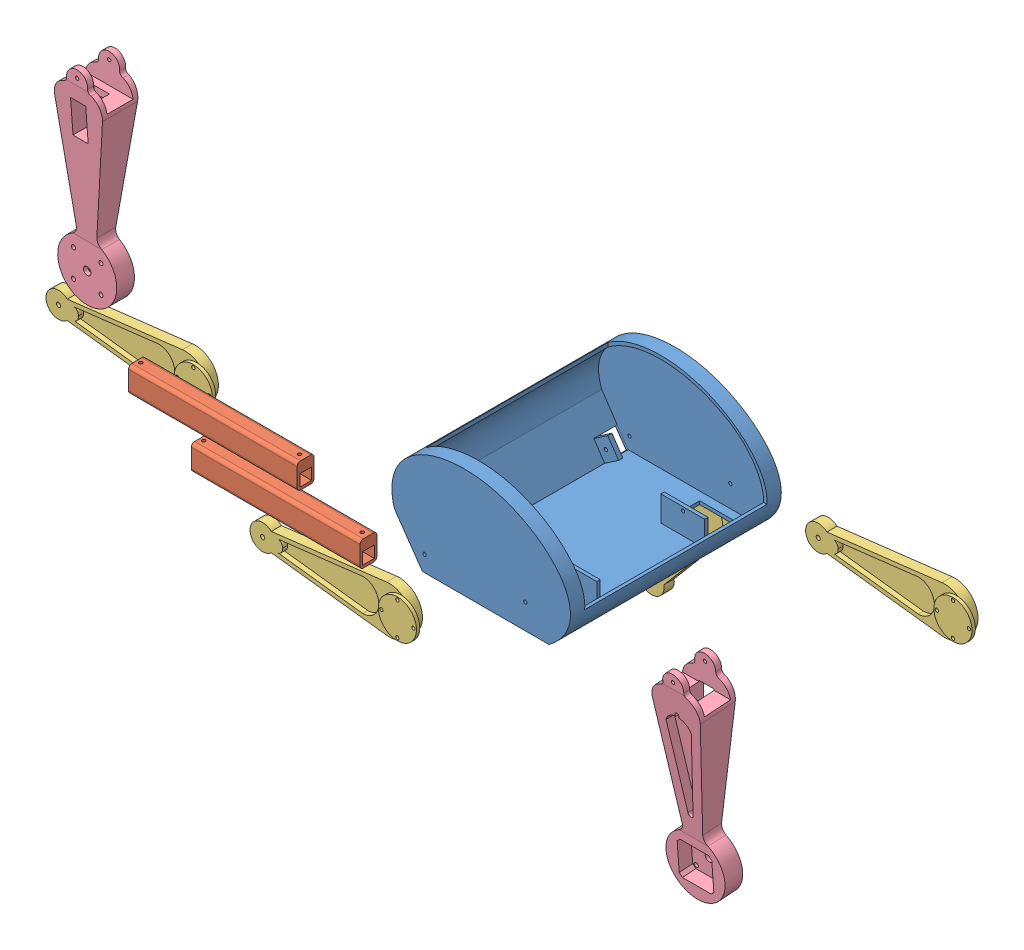
SolidWorks assembly Assem1, configuration Default. Lengths in mm.
Overall size (967.8 599.19 396.07).
9 component instances, 4 part files, 3 mates.
Components (placement in the parent):
- head2-1: head2 [Default] at (63.3878 149.356 194.8551) size (224.14 133.43 250)
- rod-1: rod [Default] at (-170.6013 277.7549 524.6912) size (200 30 20)
- rod-2: rod [Default] at (-120.5483 210.5086 500.3326) size (200 30 20)
- upleg1-1: upleg1 [Default] at (-452.3013 57.447 282.8452) size (201.32 55 16)
- upleg1-2: upleg1 [Default] at (-3.7547 146.4787 489.4308) size (201.32 55 16)
- upleg1-3: upleg1 [Default] at (87.5413 143.5361 182.8551) x (0.549505 0.83549 0) z (0 0 1) size (201.32 55 16)
- upleg1-4: upleg1 [Default] at (314.1853 134.4023 148.6234) size (201.32 55 16)
- lowleg-1: lowleg [Default] at (81.3434 -223.9244 225.5661) x (-1 0 0) z (0 0.072246 -0.997387) size (70 247.5 45)
- lowleg-2: lowleg [Default] at (-540.0226 127.854 280.5043) size (70 247.5 45)
Mates (geometry in assembly coordinates):
- Lock1: lock: unknown of head2-1; unknown of upleg1-4
- Coincident1: coincident anti-aligned: circle of head2-1; circle of upleg1-3
- Distance1: distance = 0 mm anti-aligned: plane of upleg1-3 through (92.8692 151.6368 194.8551) normal (0 0 1); plane of bipedal[1]-1 through (116.3434 -25.0303 194.8551) normal (0 0 -1)
